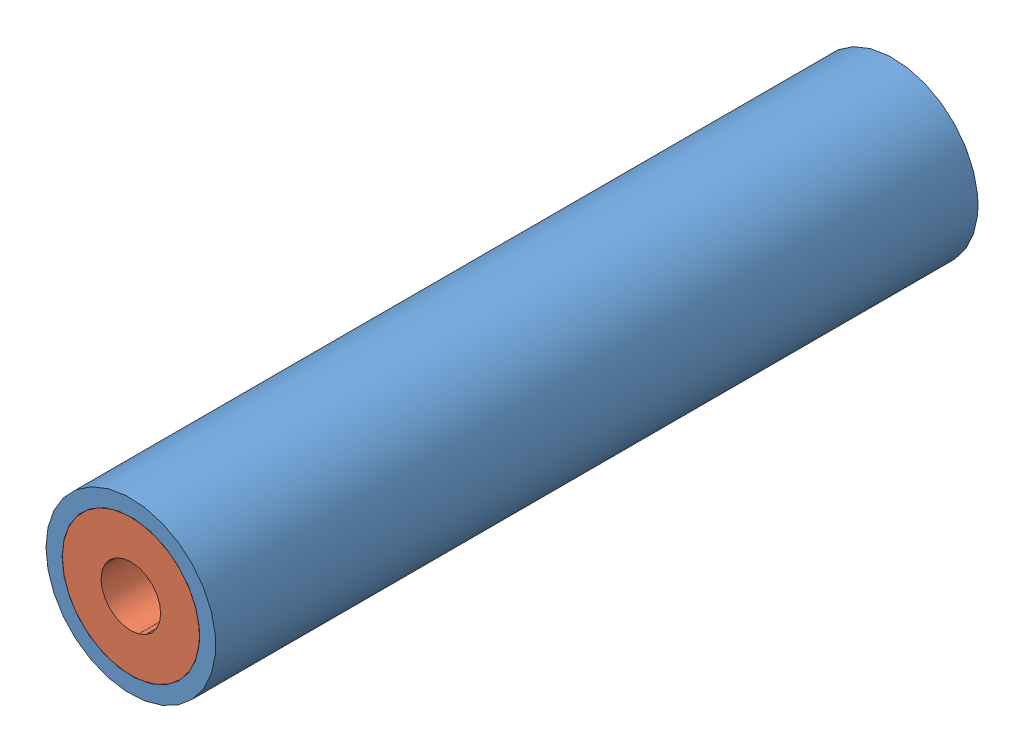
SolidWorks assembly F70 Mod. 1, configuration Default. Lengths in mm.
Overall size (33.4 33.4 150).
3 component instances, 3 part files, 4 mates.
Components (placement in the parent):
- 1 in PVC 150mm-1: 1 in PVC 150mm [Default] at (24.6146 86.6942 50.977) size (33.4 33.4 150)
- Propellant Grain-1: Propellant Grain [Default] at (24.6146 86.6942 70.977) size (26.98 26.98 130)
- Epoxy Stub-1: Epoxy Stub [Default] at (24.6146 86.6942 60.977) x (1 0 0) z (0 1 0) size (26.98 10 26.98)
Mates (geometry in assembly coordinates):
- Concentric1: concentric aligned: cylinder of 1 in PVC 150mm-1 through (24.6146 86.6942 200.977) axis (0 0 -1) radius 13.53; cylinder of Propellant Grain-1 through (24.6146 86.6942 200.977) axis (0 0 -1) radius 13.49
- Coincident1: coincident aligned: plane of 1 in PVC 150mm-1 through (24.6146 86.6942 200.977) normal (0 0 1); plane of Propellant Grain-1 through (24.6146 86.6942 200.977) normal (0 0 1)
- Concentric2: concentric anti-aligned: cylinder of 1 in PVC 150mm-1 through (24.6146 86.6942 200.977) axis (0 0 -1) radius 13.53; cylinder of Epoxy Stub-1 through (24.6146 86.6942 50.977) axis (0 0 1) radius 13.49
- Coincident2: coincident aligned: plane of 1 in PVC 150mm-1 through (24.6146 86.6942 50.977) normal (0 0 -1); plane of Epoxy Stub-1 through (24.6146 86.6942 50.977) normal (0 0 -1)
